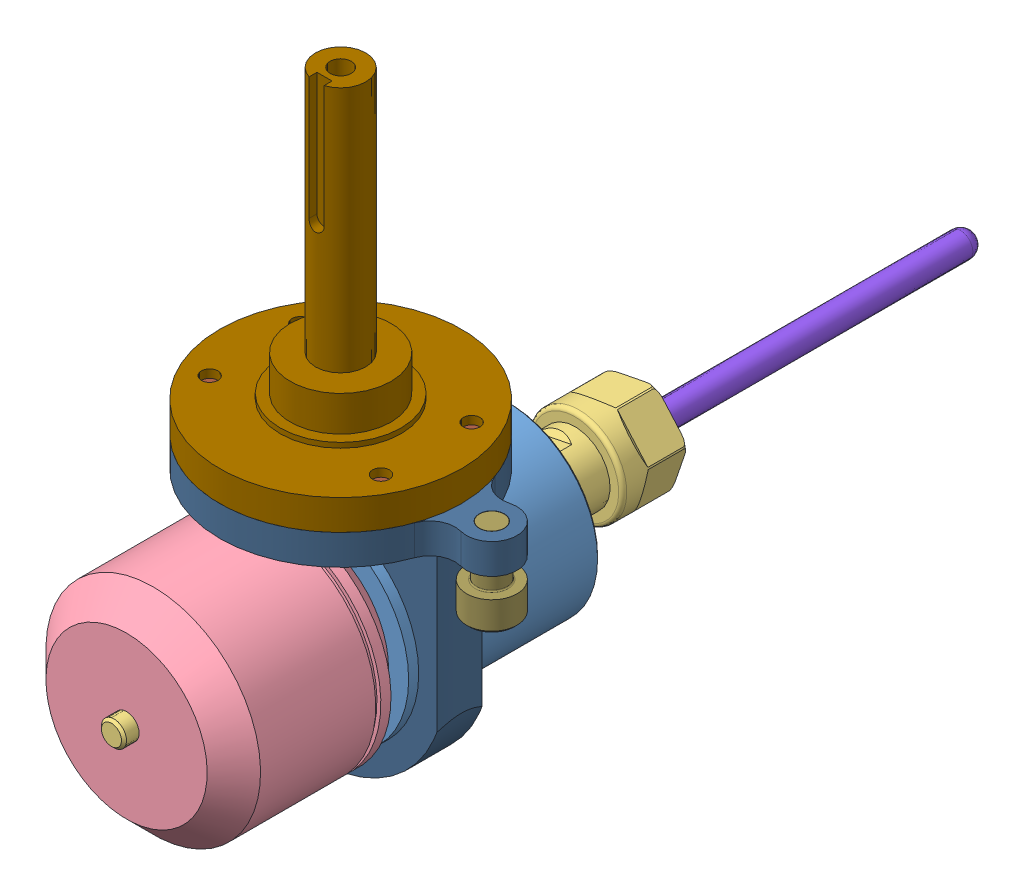
SolidWorks assembly Spindle Motor, configuration Défaut. Lengths in mm.
Overall size (59.51 117 171).
21 component instances, 12 part files, 50 mates.
Components (placement in the parent):
- Spindle Bearing Housing-1: Spindle Bearing Housing [Défaut] at (0 0 -33.5) size (40 40 40)
- Bearing Spacer-1: Bearing Spacer [Défaut] at (0 0 -22.5) x (0.17803 -0.984025 0) z (0 0 1) size (12 12 20)
- Shank Collet Chuck-1: Shank Collet Chuck [Défaut] at (0 0 45.5) x (0.194207 -0.980961 0) z (0 0 -1) size (19 19.41 105.21)
- Brushless Motor-1: Brushless Motor [Défaut] at (0 0 6.5) x (1 0 0) z (0 -1 0) size (42.6 36 42.6)
- Top Spacer-1: Top Spacer [Défaut] at (0 0 3.5) size (12 12 4)
- Ball Bearing 607-1: Ball Bearing 607 [Défaut] at (0 0 -2.5) x (0 0 1) z (-1 0 0) size (6 19 19)
- Ball Bearing 607-2: Ball Bearing 607 [Défaut] at (0 0 -28.5) x (0 0 1) z (-0.997808 -0.066178 0) size (6 19 19)
- Housing Spacer-1: Housing Spacer [Défaut] at (0 0 3.5) x (0.06441 0.997924 0) z (0 0 1) size (19 19 3)
- Ball Nose End Mill-2: Ball Nose End Mill [Défaut] at (0 0 -125.5) x (-0.024388 0.999703 0) z (0.999703 0.024388 0) size (5.1 80 5.1)
- B Axis-2: B Axis [Défaut] at (0 35 0) x (-1 0 0) z (0 1 0) size (48 48 63)
- Spindle Housing-1: Spindle Housing [Défaut] at (0 23 0) x (1 0 0) z (0 -1 0) size (59.51 48 54)
- socket head thin cap screw_din-1: socket head thin cap screw_din [DIN 7984 - M4 x 6 --- 3.9N] at (-17 24.6 -9) x (0 1 0) z (0 0 1) size (8.8 7 7)
- socket head thin cap screw_din-2: socket head thin cap screw_din [DIN 7984 - M4 x 6 --- 3.9N] at (-17 24.6 9) x (0 1 0) z (0 0 1) size (8.8 7 7)
- socket head thin cap screw_din-3: socket head thin cap screw_din [DIN 7984 - M4 x 6 --- 3.9N] at (17 24.6 9) x (0 1 0) z (0 0 1) size (8.8 7 7)
- socket head thin cap screw_din-4: socket head thin cap screw_din [DIN 7984 - M4 x 6 --- 3.9N] at (17 24.6 -9) x (0 1 0) z (0 0 1) size (8.8 7 7)
- socket head thin cap screw_din-6: socket head thin cap screw_din [DIN 7984 - M3 x 10 --- 8.5N] at (-21.5 -7.6 0) x (0 1 0) z (0 0 1) size (12 5.5 5.5)
- socket head cap screw_am-1: socket head cap screw_am [B18.3.1M - 3 x 0.5 x 40 Hex SHCS -- 18NHX] at (-8.8388 8.8388 -33.1) x (0 0 1) z (-1 0 0) size (43 5.5 5.5)
- socket head cap screw_am-2: socket head cap screw_am [B18.3.1M - 3 x 0.5 x 40 Hex SHCS -- 18NHX] at (-8.8388 -8.8388 -33.1) x (0 0 1) z (-1 0 0) size (43 5.5 5.5)
- socket head cap screw_am-3: socket head cap screw_am [B18.3.1M - 3 x 0.5 x 40 Hex SHCS -- 18NHX] at (8.8388 8.8388 -33.1) x (0 0 1) z (-1 0 0) size (43 5.5 5.5)
- socket head cap screw_am-4: socket head cap screw_am [B18.3.1M - 3 x 0.5 x 40 Hex SHCS -- 18NHX] at (8.8388 -8.8388 -33.1) x (0 0 1) z (-1 0 0) size (43 5.5 5.5)
- socket head cap screw_am-5: socket head cap screw_am [B18.3.1M - 6 x 1.0 x 10 Hex SHCS -- 10NHX] at (30 13 0) x (0 1 0) z (0 0 1) size (16 10 10)
Mates (geometry in assembly coordinates):
- Coaxiale4: concentric anti-aligned: cylinder of Bearing Spacer-1 through (0 0 -2.5) axis (0 0 -1) radius 6; cylinder of 1 x Shank Collet Chuck-1 through (0 0 -34.5) axis (0 0 1) radius 4
- Concentric1: concentric anti-aligned: cylinder of 1 x Shank Collet Chuck-1 through (0 0 -34.5) axis (0 0 1) radius 4; cylinder of Brushless Motor-1 through (0 0 6.5) axis (0 0 -1) radius 2.5
- Coincident6: coincident: plane of ? through (83.3313 -30.816 57.0781) normal (0 0 -1); plane of ? through (83.3313 -40.416 57.0781) normal (0 0 1)
- Concentric4: concentric anti-aligned: cylinder of 1 x Shank Collet Chuck-1 through (0 0 -34.5) axis (0 0 1) radius 4; cylinder of Top Spacer-1 through (0 0 7.5) axis (0 0 -1) radius 4
- Coincident7: coincident anti-aligned: plane of Brushless Motor-1 through (2.5 0 7.5) normal (0 0 -1); plane of Top Spacer-1 through (0 0 7.5) normal (0 0 1)
- Coincident8: coincident: plane of ? through (83.3313 -30.816 106.0781) normal (0 0 1); plane of Top Spacer-1 through (0 0 3.5) normal (0 0 -1)
- Concentric7: concentric aligned: cylinder of Brushless Motor-1 through (0 0 6.5) axis (0 0 -1) radius 21.3; cylinder of ? through (83.3313 -40.416 85.0781) axis (0 0 -1) radius 21
- Coincident10: coincident anti-aligned: plane of Brushless Motor-1 through (8 0 6.5) normal (0 0 -1); plane of ? through (75.9415 -43.4804 113.0781) normal (0 0 1)
- Concentric8: concentric anti-aligned: cylinder of 1 x Shank Collet Chuck-1 through (0 0 -49.916) axis (0 0 1) radius 3.5; cylinder of Ball Bearing 607-2 through (0 0 -28.5) axis (0 0 -1) radius 3.5
- Concentric9: concentric anti-aligned: cylinder of 1 x Shank Collet Chuck-1 through (0 0 -49.916) axis (0 0 1) radius 3.5; cylinder of Ball Bearing 607-1 through (0 0 -2.5) axis (0 0 -1) radius 3.5
- Coincident11: coincident anti-aligned: plane of Top Spacer-1 through (0 0 3.5) normal (0 0 -1); plane of Ball Bearing 607-1 through (0 3.8 3.5) normal (0 0 1)
- Coincident12: coincident anti-aligned: plane of 1 x Shank Collet Chuck-1 through (0 0 -28.5) normal (0 0 1); plane of Ball Bearing 607-2 through (-0.2515 3.7917 -28.5) normal (0 0 -1)
- Concentric10: concentric aligned: cylinder of 1 x Shank Collet Chuck-1 through (0 0 -49.916) axis (0 0 1) radius 3.5; cylinder of 1 x Spindle Bearing Housing-1 through (0 0 -60.3701) axis (0 0 1) radius 9.5
- Coincident13: coincident anti-aligned: plane of 1 x Spindle Bearing Housing-1 through (0 0 -28.5) normal (0 0 1); plane of Ball Bearing 607-2 through (-0.546 8.2319 -28.5) normal (0 0 -1)
- Coincident14: coincident anti-aligned: plane of Brushless Motor-1 through (8 0 6.5) normal (0 0 -1); plane of 1 x Spindle Bearing Housing-1 through (0 0 6.5) normal (0 0 1)
- Concentric11: concentric aligned: circle of Brushless Motor-1; cylinder of 1 x Spindle Bearing Housing-1 through (8.8388 -8.8388 -33.5) axis (0 0 -1) radius 3.25
- Coincident15: coincident anti-aligned: plane of Bearing Spacer-1 through (0 0 -22.5) normal (0 0 -1); plane of Ball Bearing 607-2 through (-0.2515 3.7917 -22.5) normal (0 0 1)
- Concentric12: concentric aligned: cylinder of 1 x Spindle Bearing Housing-1 through (0 0 6.5) axis (0 0 -1) radius 18; cylinder of 1 x Housing Spacer-1 through (0 0 6.5) axis (0 0 -1) radius 9.5
- Coincident16: coincident anti-aligned: plane of Brushless Motor-1 through (8 0 6.5) normal (0 0 -1); plane of 1 x Housing Spacer-1 through (0 0 6.5) normal (0 0 1)
- Concentric14: concentric aligned: cylinder of 1 x Shank Collet Chuck-1 through (0 0 -47.5) axis (0 0 -1) radius 2.6; cylinder of Ball Nose End Mill-2 through (0 0 -125.5) axis (0 0 -1) radius 2.55
- Distance1: distance = 130 mm anti-aligned: plane of 1 x Spindle Bearing Housing-1 through (0 0 4.5) normal (0 0 -1); plane of Ball Nose End Mill-2 through (0 0 -125.5) normal (0 0 1)
- Coïncidente1: coincident anti-aligned: plane of B Axis-2 through (0 29 0) normal (0 -1 0); plane of Spindle Housing-1 through (0 29 0) normal (0 1 0)
- Coaxiale5: concentric anti-aligned: cylinder of B Axis-2 through (0 29 0) axis (0 1 0) radius 24; cylinder of Spindle Housing-1 through (0 29 0) axis (0 -1 0) radius 24
- Coaxiale6: concentric aligned: cylinder of 1 x Spindle Bearing Housing-1 through (0 0 6.5) axis (0 0 -1) radius 18; cylinder of Spindle Housing-1 through (0 0 4.5) axis (0 0 -1) radius 18.05
- Coïncidente2: coincident anti-aligned: plane of 1 x Spindle Bearing Housing-1 through (0 0 4.5) normal (0 0 -1); plane of Spindle Housing-1 through (0 23 4.5) normal (0 0 1)
- Coaxiale7: concentric aligned: cylinder of B Axis-2 through (17 29 -9) axis (0 -1 0) radius 1.65; cylinder of Spindle Housing-1 through (17 23 -9) axis (0 -1 0) radius 4
- Distance2: distance = 4.5 mm anti-aligned: plane of 1 x Spindle Bearing Housing-1 through (0 0 4.5) normal (0 0 -1); plane of assembly through (0 0 0) normal (0 0 1)
- Coïncidente3: coincident aligned: plane of 1 x Spindle Bearing Housing-1 through (0 0 -33.5) normal (1 0 0); plane of assembly through (0 0 0) normal (1 0 0)
- Coïncidente4: coincident aligned: plane of 1 x Spindle Bearing Housing-1 through (0 0 -33.5) normal (0 1 0); plane of assembly through (0 0 0) normal (0 1 0)
- Parallèle1: parallel aligned: plane of B Axis-2 through (0 35 0) normal (0 1 0); plane of assembly through (0 0 0) normal (0 1 0)
- Coaxiale8: concentric aligned: cylinder of Spindle Housing-1 through (-17 23 -9) axis (0 -1 0) radius 4; cylinder of socket head thin cap screw_din-1 through (-17 -7.15 -9) axis (0 -1 0) radius 3.5
- Coïncidente5: coincident anti-aligned: plane of Spindle Housing-1 through (-14.75 27.4 -9) normal (0 -1 0); plane of socket head thin cap screw_din-1 through (-20.5 27.4 -9) normal (0 1 0)
- Coaxiale9: concentric aligned: cylinder of Spindle Housing-1 through (-17 23 9) axis (0 -1 0) radius 4; cylinder of socket head thin cap screw_din-2 through (-17 -7.15 9) axis (0 -1 0) radius 3.5
- Coïncidente6: coincident anti-aligned: plane of Spindle Housing-1 through (-14.75 27.4 9) normal (0 -1 0); plane of socket head thin cap screw_din-2 through (-20.5 27.4 9) normal (0 1 0)
- Coaxiale10: concentric aligned: cylinder of Spindle Housing-1 through (17 23 9) axis (0 -1 0) radius 4; cylinder of socket head thin cap screw_din-3 through (17 -7.15 9) axis (0 -1 0) radius 3.5
- Coïncidente7: coincident anti-aligned: plane of Spindle Housing-1 through (19.25 27.4 9) normal (0 -1 0); plane of socket head thin cap screw_din-3 through (13.5 27.4 9) normal (0 1 0)
- Coaxiale11: concentric aligned: cylinder of Spindle Housing-1 through (17 23 -9) axis (0 -1 0) radius 4; cylinder of socket head thin cap screw_din-4 through (17 -7.15 -9) axis (0 -1 0) radius 3.5
- Coïncidente8: coincident anti-aligned: plane of Spindle Housing-1 through (19.25 27.4 -9) normal (0 -1 0); plane of socket head thin cap screw_din-4 through (13.5 27.4 -9) normal (0 1 0)
- Coaxiale12: concentric aligned: cylinder of Spindle Housing-1 through (-21.5 -21 0) axis (0 -1 0) radius 1.7; cylinder of socket head thin cap screw_din-6 through (-21.5 -39.35 0) axis (0 -1 0) radius 2.75
- Coïncidente10: coincident anti-aligned: plane of Spindle Housing-1 through (-19.8 -5.6 0) normal (0 -1 0); plane of socket head thin cap screw_din-6 through (-24.25 -5.6 0) normal (0 1 0)
- Coaxiale15: concentric aligned: cylinder of 1 x Spindle Bearing Housing-1 through (-8.8388 8.8388 -33.5) axis (0 0 -1) radius 1.7; cylinder of socket head cap screw_am-1 through (-8.8388 8.8388 -64.85) axis (0 0 -1) radius 2.75
- Coïncidente13: coincident anti-aligned: plane of 1 x Spindle Bearing Housing-1 through (-7.1388 8.8388 -30.1) normal (0 0 -1); plane of socket head cap screw_am-1 through (-8.8388 11.5888 -30.1) normal (0 0 1)
- Coaxiale16: concentric aligned: cylinder of 1 x Spindle Bearing Housing-1 through (-8.8388 -8.8388 -33.5) axis (0 0 -1) radius 1.7; cylinder of socket head cap screw_am-2 through (-8.8388 -8.8388 -64.85) axis (0 0 -1) radius 2.75
- Coïncidente14: coincident anti-aligned: plane of 1 x Spindle Bearing Housing-1 through (-7.1388 -8.8388 -30.1) normal (0 0 -1); plane of socket head cap screw_am-2 through (-8.8388 -6.0888 -30.1) normal (0 0 1)
- Coaxiale17: concentric aligned: cylinder of 1 x Spindle Bearing Housing-1 through (8.8388 8.8388 -33.5) axis (0 0 -1) radius 1.7; cylinder of socket head cap screw_am-3 through (8.8388 8.8388 -64.85) axis (0 0 -1) radius 2.75
- Coïncidente15: coincident anti-aligned: plane of 1 x Spindle Bearing Housing-1 through (10.5388 8.8388 -30.1) normal (0 0 -1); plane of socket head cap screw_am-3 through (8.8388 11.5888 -30.1) normal (0 0 1)
- Coaxiale18: concentric aligned: cylinder of 1 x Spindle Bearing Housing-1 through (8.8388 -8.8388 -33.5) axis (0 0 -1) radius 1.7; cylinder of socket head cap screw_am-4 through (8.8388 -8.8388 -64.85) axis (0 0 -1) radius 2.75
- Coïncidente16: coincident anti-aligned: plane of 1 x Spindle Bearing Housing-1 through (10.5388 -8.8388 -30.1) normal (0 0 -1); plane of socket head cap screw_am-4 through (8.8388 -6.0888 -30.1) normal (0 0 1)
- Coaxiale19: concentric aligned: cylinder of Spindle Housing-1 through (30 23 0) axis (0 -1 0) radius 2.5; cylinder of socket head cap screw_am-5 through (30 -18.75 0) axis (0 -1 0) radius 5
- Distance3: distance = 4 mm anti-aligned: plane of Spindle Housing-1 through (0 23 0) normal (0 -1 0); plane of socket head cap screw_am-5 through (25 19 0) normal (0 1 0)
